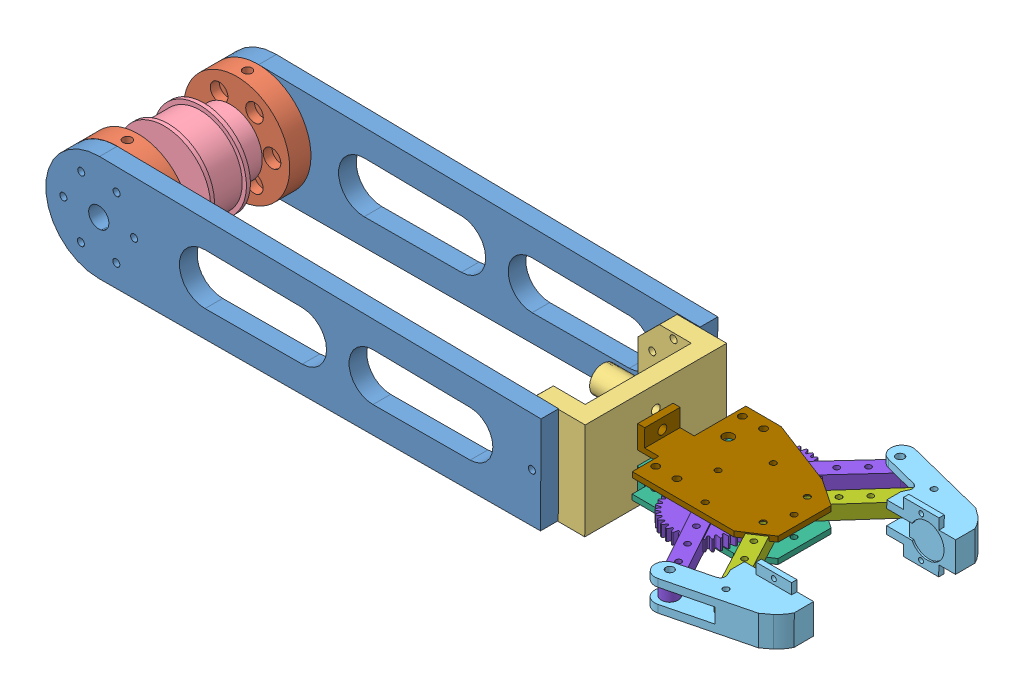
SolidWorks assembly khau3, configuration Default. Lengths in mm.
Overall size (433.14 120.44 151.45).
15 component instances, 9 part files, 17 mates.
Components (placement in the parent):
- khau3-1: khau3 [Default] at (385.3786 194.0729 443.2577) x (-0.999989 0.004704 0) z (0.004704 0.999989 0) size (280 10 60)
- dem truc-1: dem truc [Default] at (351.7169 184.2759 453.2577) x (-0.999989 0.004704 0) z (0.004704 0.999989 0) size (60 12 60)
- khau3-2: khau3 [Default] at (385.283 174.1562 543.2577) x (-0.999988 0.004897 0) z (-0.004897 -0.999988 0) size (280 10 60)
- dem truc-2: dem truc [Default] at (351.7169 184.2759 533.2577) x (-0.999988 0.004897 0) z (-0.004897 -0.999988 0) size (60 12 60)
- gripper_adapter-2: gripper_adapter [Default] at (616.712 182.6275 493.2577) x (0 0 -1) z (0.0048 0.999988 0) size (80 40 55)
- pulleykhop3-1: pulleykhop3 [Default] at (351.7169 184.2759 500.9496) x (1 0 0) z (0 1 0) size (52.5 37.5 52.5)
- Assem1-1: Assem1 [Default] at (688.0831 140.4657 525.8877) x (-0.999988 0.0048 0) z (0 0 -1) size (140.94 34 151.45)
  - bar-1: bar [Default] at (-38.3643 29.7687 -6.541) x (0.999985 0 -0.005467) z (0 1 0) size (63.11 32.89 29)
  - bar-2: bar [Default] at (-48.2663 46.7687 64.6287) x (0.999998 0 -0.001801) z (0 -1 0) size (63.11 32.89 29)
  - Partx_2-1: Partx_2 [Default] at (4.5693 31.0687 31.5676) size (87.5 13 64.28)
  - part1-1: part1 [Default] at (-13.8461 40.4187 -2.55) x (0.883068 0 -0.469245) z (0.469245 0 0.883068) size (9.65 8 60.45)
  - part1-2: part1 [Default] at (-18.7303 40.4187 63.9278) x (-0.749915 0 -0.661534) z (0.661534 0 -0.749915) size (9.65 8 60.45)
  - Part2-1: Part2 [GearTrax] at (24.0727 38.0687 51.6299) x (-0.73953 0 -0.673124) z (0 1 0) size (40.13 75.63 8)
  - Part2-2: Part2 [GearTrax] at (24.0727 38.0687 13.1299) x (0.876315 0 -0.481738) z (0 1 0) size (40.13 75.63 8)
  - Partx-3: Partx [Default] at (4.5693 42.0687 31.5676) size (87.5 13 64.26)
Mates (geometry in assembly coordinates):
- Concentric1: concentric: cylinder of assembly; cylinder of assembly; cylinder of khau3-1 through (361.7982 201.5491 453.2577) axis (0 0 -1) radius 2; cylinder of dem truc-1 through (361.7982 201.5491 460.2577) axis (0 0 1) radius 5
- Concentric2: concentric: cylinder of assembly; cylinder of assembly; cylinder of khau3-1 through (351.7169 184.2759 453.2577) axis (0 0 -1) radius 5.75; cylinder of dem truc-1 through (351.7169 184.2759 465.2577) axis (0 0 -1) radius 6
- Coincident1: coincident: plane of assembly; plane of assembly; plane of khau3-1 through (351.7169 184.2759 453.2577) normal (0 0 1); plane of dem truc-1 through (351.7169 184.2759 453.2577) normal (0 0 -1)
- Concentric3: concentric: cylinder of assembly; cylinder of assembly; cylinder of khau3-2 through (351.7169 184.2759 533.2577) axis (0 0 1) radius 5.75; cylinder of dem truc-2 through (351.7169 184.2759 521.2577) axis (0 0 1) radius 6
- Concentric4: concentric: cylinder of assembly; cylinder of assembly; cylinder of khau3-2 through (361.6319 166.9066 533.2577) axis (0 0 1) radius 2; cylinder of dem truc-2 through (361.6319 166.9066 526.2577) axis (0 0 -1) radius 5
- Coincident2: coincident: plane of assembly; plane of assembly; plane of khau3-2 through (351.7169 184.2759 533.2577) normal (0 0 -1); plane of dem truc-2 through (351.7169 184.2759 533.2577) normal (0 0 1)
- Parallel1: parallel: plane of assembly; plane of assembly; plane of khau3-1 through (601.846 210.5755 453.2577) normal (0.014805 0.99989 0); plane of khau3-2 through (601.846 210.5755 533.2577) normal (0.014805 0.99989 0)
- Concentric19: concentric: cylinder of assembly; cylinder of assembly; cylinder of dem truc-1 through (351.7169 184.2759 465.2577) axis (0 0 -1) radius 6; cylinder of dem truc-2 through (351.7169 184.2759 521.2577) axis (0 0 1) radius 6
- Distance4: distance = 80 mm: plane of assembly; plane of assembly; plane of khau3-2 through (351.7169 184.2759 533.2577) normal (0 0 -1); plane of khau3-1 through (351.7169 184.2759 453.2577) normal (0 0 1)
- Distance6: distance = 15 mm: plane of assembly; plane of assembly; plane of khau3-2 through (601.846 210.5755 533.2577) normal (0.999988 -0.0048 0); plane of gripper_adapter-2 through (616.712 182.6275 493.2577) normal (0.999988 -0.0048 0)
- Coincident7: coincident: plane of assembly; plane of assembly; plane of khau3-1 through (351.7169 184.2759 453.2577) normal (0 0 1); plane of gripper_adapter-2 through (606.8441 210.1752 453.2577) normal (0 0 -1)
- Concentric22: concentric: cylinder of assembly; cylinder of assembly; cylinder of khau3-1 through (596.7141 183.0993 453.2577) axis (0 0 -1) radius 2; cylinder of gripper_adapter-2 through (596.7141 183.0993 453.2577) axis (0 0 1) radius 2
- Concentric23: concentric: cylinder of assembly; cylinder of assembly; cylinder of dem truc-2 through (351.7169 184.2759 521.2577) axis (0 0 1) radius 6; cylinder of pulleykhop3-1 through (351.7169 184.2759 507.7577) axis (0 0 -1) radius 7.5
- Distance7: distance = 15 mm: plane of assembly; plane of assembly; plane of pulleykhop3-1 through (351.7169 184.2759 506.2577) normal (0 0 1); plane of dem truc-2 through (351.7169 184.2759 521.2577) normal (0 0 -1)
- Coincident9: coincident: plane of assembly; plane of assembly; plane of gripper_adapter-2 through (616.712 182.6275 493.2577) normal (0.999988 -0.0048 0); plane of Assem1-1/Partx-3 through (616.7756 195.8774 483.5077) normal (-0.999988 0.0048 0)
- Coincident10: coincident: plane of assembly; plane of assembly; plane of gripper_adapter-2 through (611.6605 171.9016 503.5077) normal (0.0048 0.999988 0); plane of Assem1-1/Partx_2-1 through (683.663 171.556 494.3201) normal (-0.0048 -0.999988 0)
- Coincident11: coincident: plane of assembly; plane of assembly; plane of gripper_adapter-2 through (611.6605 171.9016 503.5077) normal (0 0 -1); plane of Assem1-1/Partx_2-1 through (683.6774 174.556 503.5077) normal (0 0 1)
